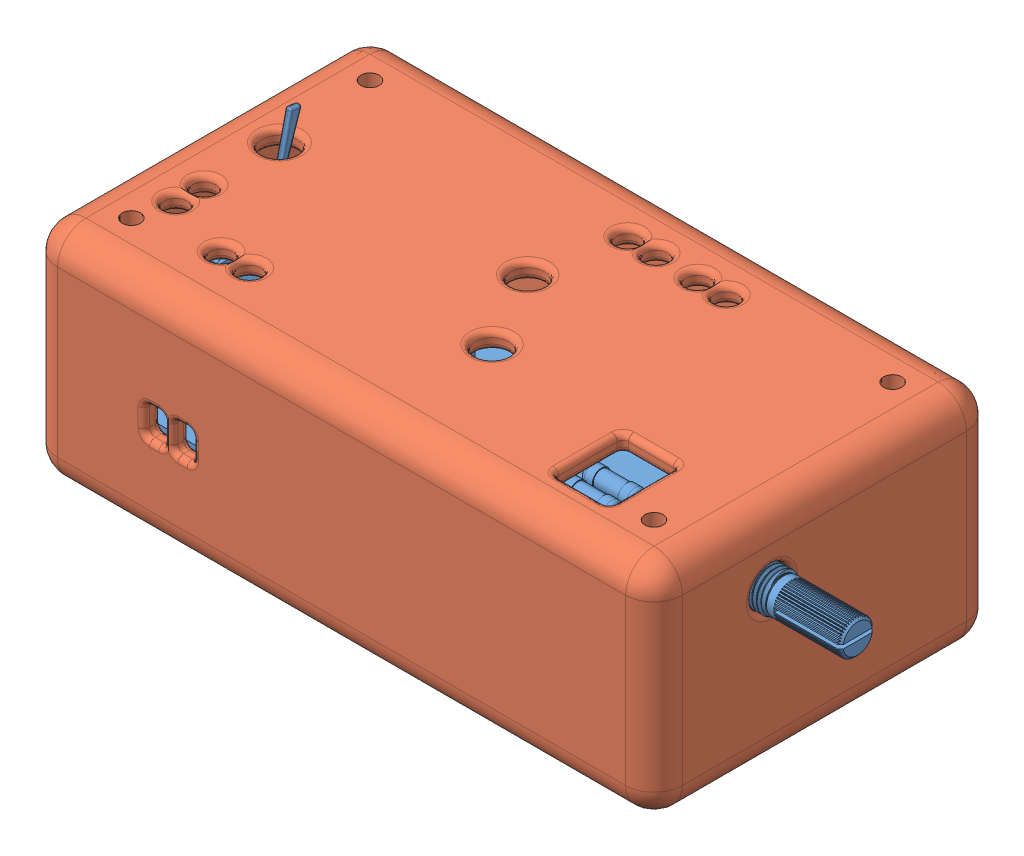
SolidWorks assembly Ensamblaje2, configuration Predeterminado. Lengths in mm.
Overall size (125.19 43.53 60.18).
2 component instances, 2 part files, 3 mates.
Components (placement in the parent):
- 555-1: 555 [Default] at origin size (120.1 39.19 51.07)
- Gabinete-1: Gabinete [Predeterminado] at (0 0.755 0) x (1 0 0) z (0 1 0) size (110.09 60.18 39.13)
Mates (geometry in assembly coordinates):
- Coincidente2: coincident: plane of 555-1 through (50 -0.755 -25) normal (0 -1 0); plane of Gabinete-1 through (-46 -0.755 21) normal (0 1 0)
- Concéntrica3: concentric: circle of 555-1; circle of Gabinete-1
- Concéntrica4: concentric aligned: cylinder of 555-1 through (46 0.755 -21) axis (0 -1 0) radius 1.6; cylinder of Gabinete-1 through (46 -0.755 -21) axis (0 -1 0) radius 1.6
